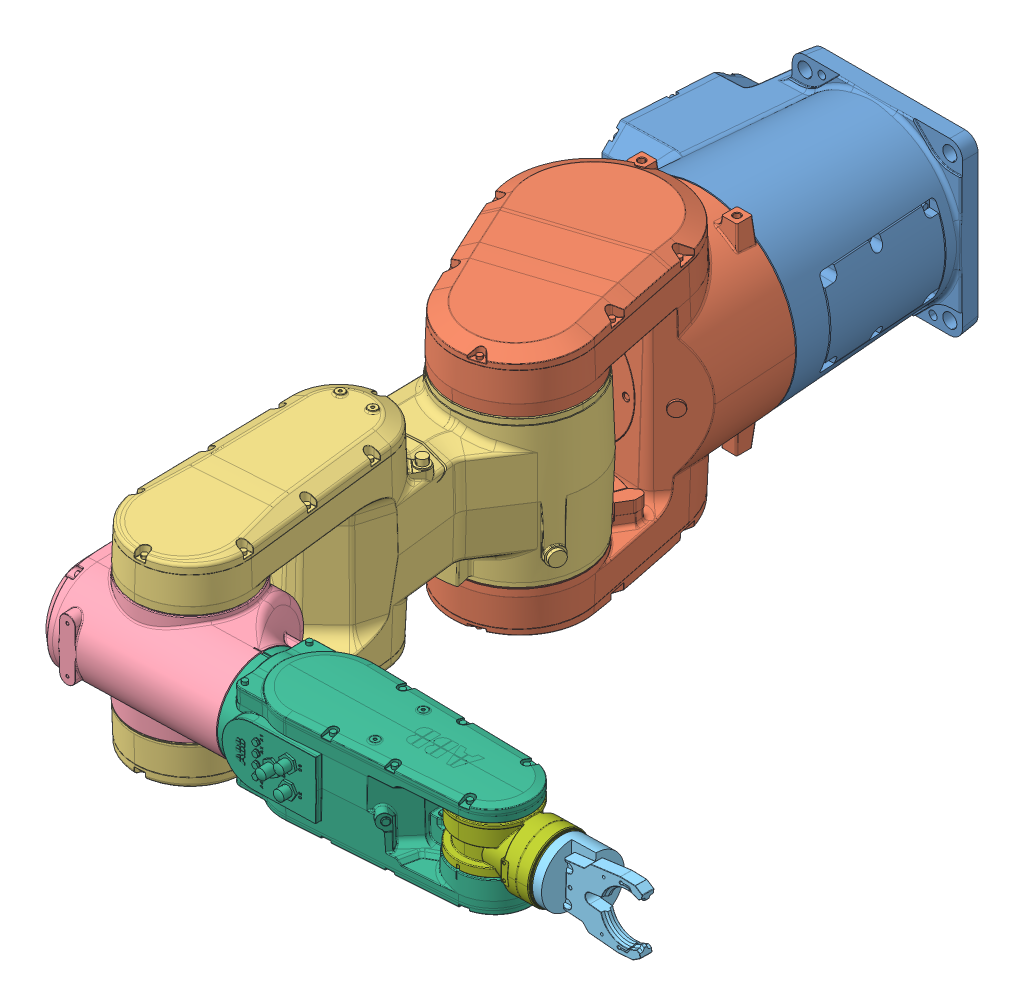
SolidWorks assembly Robot_assemblato, configuration Default. Lengths in mm.
Overall size (872.72 340.45 1089.84).
7 component instances, 7 part files, 14 mates.
Components (placement in the parent):
- link0-rear cable_ORIENTATO-1: link0-rear cable_ORIENTATO [Default] at origin size (319.94 284.94 254.63)
- link1_900_DH-4: link1_900_DH [Default] at (48.3941 -3.3044 544) x (0.999999 -0.00131 0) z (-0.00131 -0.999999 0) size (329.17 404.31 340.02)
- link2_900-1: link2_900 [Default] at (45.0256 -1.054 968.9681) x (-0.011706 0.000015 0.999931) z (-0.00131 -0.999999 0) size (601.23 189.02 278)
- link3-5: link3 [Default] at (46.368 -0.0566 1008.9528) x (0.027272 -0.000036 0.999628) z (0.999627 -0.00131 -0.027272) size (197.44 160.88 236.33)
- Gruppo_Endeffector-1: Gruppo_Endeffector [Default] at (647.0543 -0.7289 996.9961) x (0.022346 0.037453 0.999048) z (0.99975 -0.001323 -0.022312) size (78.97 84.99 125.12)
- link4_900-2: link4_900 [Default] at (470.9558 0.1922 997.3889) x (0.027269 -0.002773 0.999624) z (-0.001385 -0.999995 -0.002736) size (148.27 345.08 126.82)
- link5-foundry.step-3: link5-foundry.step [Default] at (470.9457 -0.9693 997.3631) x (0.022308 -0.002766 0.999747) z (0.99975 -0.001323 -0.022312) size (123.45 84.83 136.6)
Mates (geometry in assembly coordinates):
- Coincidente3: coincident anti-aligned: plane of link0-rear cable_ORIENTATO-1 through (0 0 254) normal (0 0 1); plane of link1_900_DH-4 through (-78.7201 -106.9208 254) normal (0 0 -1)
- Concentrico3: concentric aligned: circle of link0-rear cable_ORIENTATO-1; circle of link1_900_DH-4
- Coincidente4: coincident anti-aligned: plane of link1_900_DH-4 through (49.8683 -100.5654 624.7279) normal (0.00131 0.999999 0); plane of link2_900-1 through (49.8683 -100.5654 544) normal (-0.00131 -0.999999 0)
- Concentrico4: concentric anti-aligned: circle of link1_900_DH-4; circle of link2_900-1
- Coincidente9: coincident anti-aligned: plane of link2_900-1 through (50.7137 69.9336 1048.7748) normal (-0.00131 -0.999999 0); plane of link3-5 through (45.1165 69.941 968.9709) normal (0.00131 0.999999 0)
- Coincidente10: coincident anti-aligned: plane of link2_900-1 through (50.7137 69.9336 1048.7748) normal (-0.00131 -0.999999 0); plane of link3-5 through (45.1165 69.941 968.9709) normal (0.00131 0.999999 0)
- Coincidente11: coincident anti-aligned: plane of link2_900-1 through (50.7137 69.9336 1048.7748) normal (-0.00131 -0.999999 0); plane of link3-5 through (45.1165 69.941 968.9709) normal (0.00131 0.999999 0)
- Concentrico6: concentric anti-aligned: circle of link2_900-1; circle of link3-5
- Concentrico7: concentric aligned: circle of link3-5; circle of link4_900-2
- Coincidente12: coincident anti-aligned: plane of link3-5 through (175.5675 -0.23 1005.4242) normal (0.999627 -0.00131 -0.027272); plane of link4_900-2 through (175.4774 -65.2297 1005.2464) normal (-0.999627 0.00131 0.027272)
- Coincidente13: coincident anti-aligned: plane of link4_900-2 through (470.931 -19.6169 997.3133) normal (0.001385 0.999995 0.002736); plane of link5-foundry.step-3 through (470.931 -19.6169 997.3133) normal (-0.001385 -0.999995 -0.002736)
- Concentrico8: concentric anti-aligned: circle of link4_900-2; circle of link5-foundry.step-3
- Coincidente14: coincident anti-aligned: plane of Gruppo_Endeffector-1 through (554.9363 -0.7281 995.4911) normal (-0.99975 0.001323 0.022312); plane of link5-foundry.step-3 through (554.8899 -34.228 995.3994) normal (0.99975 -0.001323 -0.022312)
- Concentrico9: concentric aligned: circle of Gruppo_Endeffector-1; circle of link5-foundry.step-3
